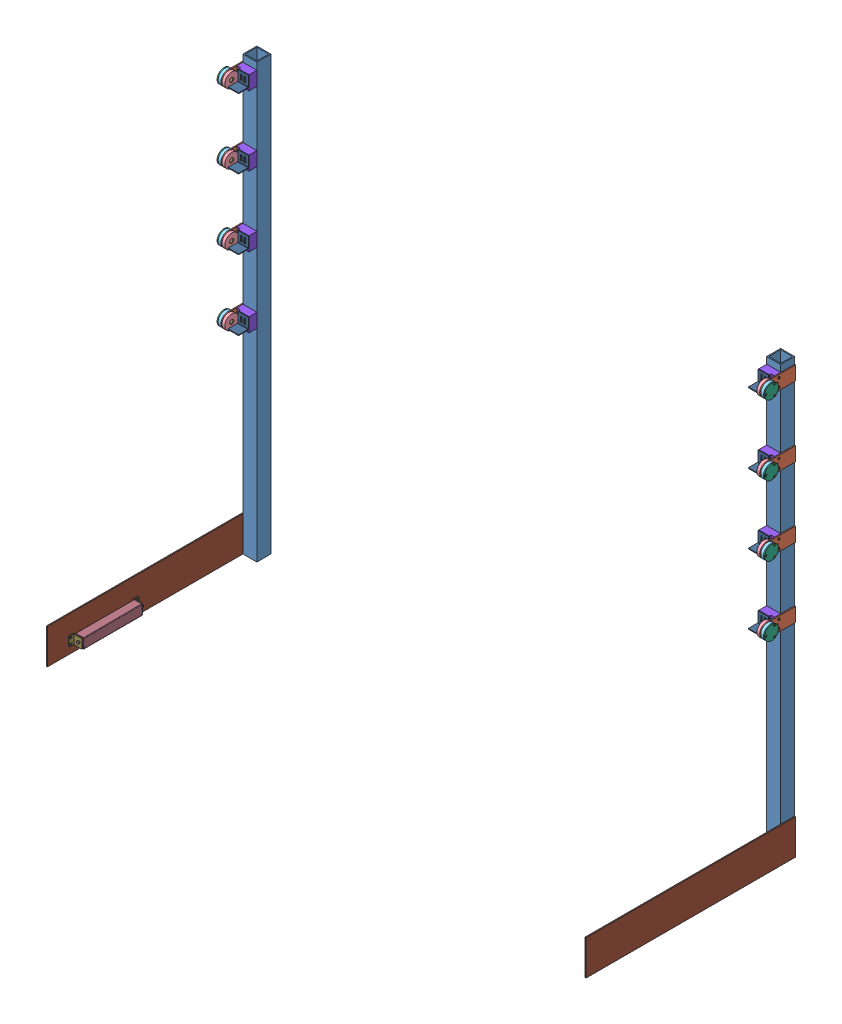
SolidWorks assembly NikeLimbo, configuration Default. Lengths in mm.
Overall size (1571.3 1240 600).
140 component instances, 13 part files, 50 mates.
Components (placement in the parent):
- Frame-1: Frame [Default] at (-24.774 0 -3.5462) size (40 1240 40)
- Frame-2: Frame [Default] at (1475.226 0 -3.5462) size (40 1240 40)
- PoleMount-1: PoleMount [Default] at (-47.774 1005.7046 22.3106) x (0 0 -1) z (0 -1 0) size (100 55.65 40)
  - LEDFixture-1: LEDFixture [Default] at (-4.1432 0 5.1297) size (100 3 40)
  - LED-1: LED [Default] at (-34.1432 3 5.1297) x (0 0 1) z (-1 0 0) size (25 5.3 20)
  - LED-2: LED [Default] at (-34.1432 0 5.1297) x (0 0 -1) z (-1 0 0) size (25 5.3 20)
  - LEDCoverInternal-1: LEDCoverInternal [Default] at origin size (40 8 40)
  - LEDCoverExternal-1: LEDCoverExternal [Default] at origin size (40 8 40)
  - LEDDiffuser-1: LEDDiffuser [Default] at origin size (40 3 40)
  - socket button head screw_iso-1: socket button head screw_iso [ISO 7380 - M3 x 6 --- 6N] at (-25.6432 -12.65 19.8521) x (0 1 0) z (0 0 1) size (7.65 5.7 5.7)
  - socket button head screw_iso-3: socket button head screw_iso [ISO 7380 - M3 x 6 --- 6N] at (-51.1432 -12.65 5.1297) x (0 1 0) z (0 0 1) size (7.65 5.7 5.7)
  - socket button head screw_iso-4: socket button head screw_iso [ISO 7380 - M3 x 6 --- 6N] at (-25.6432 -12.65 -9.5927) x (0 1 0) z (0 0 1) size (7.65 5.7 5.7)
  - MountBlock-1: MountBlock [Default] at origin size (22.5 40 40)
  - hexagon socket button head screw_jis-1: hexagon socket button head screw_jis [JIS B 1174 M3 x 6 (6) --N] at (-2.1432 -1.65 -6.8703) x (0 1 0) z (0 0 1) size (7.65 5.7 5.7)
  - hexagon socket button head screw_jis-2: hexagon socket button head screw_jis [JIS B 1174 M3 x 6 (6) --N] at (-2.1432 -1.65 17.1297) x (0 1 0) z (0 0 1) size (7.65 5.7 5.7)
  - hexagon socket button head screw_jis-3: hexagon socket button head screw_jis [JIS B 1174 M3 x 6 (6) --N] at (-20.2932 23 5.1297) size (7.65 5.7 5.7)
  - hexagon socket button head screw_jis-4: hexagon socket button head screw_jis [JIS B 1174 M3 x 6 (6) --N] at (-20.2932 33 5.1297) size (7.65 5.7 5.7)
- PoleMount-2: PoleMount [Default] at (-47.774 805.4055 22.3106) x (0 0 -1) z (0 -1 0) size (100 55.65 40)
  - LEDFixture-1: LEDFixture [Default] at (-4.1432 0 5.1297) size (100 3 40)
  - LED-1: LED [Default] at (-34.1432 3 5.1297) x (0 0 1) z (-1 0 0) size (25 5.3 20)
  - LED-2: LED [Default] at (-34.1432 0 5.1297) x (0 0 -1) z (-1 0 0) size (25 5.3 20)
  - LEDCoverInternal-1: LEDCoverInternal [Default] at origin size (40 8 40)
  - LEDCoverExternal-1: LEDCoverExternal [Default] at origin size (40 8 40)
  - LEDDiffuser-1: LEDDiffuser [Default] at origin size (40 3 40)
  - socket button head screw_iso-1: socket button head screw_iso [ISO 7380 - M3 x 6 --- 6N] at (-25.6432 -12.65 19.8521) x (0 1 0) z (0 0 1) size (7.65 5.7 5.7)
  - socket button head screw_iso-3: socket button head screw_iso [ISO 7380 - M3 x 6 --- 6N] at (-51.1432 -12.65 5.1297) x (0 1 0) z (0 0 1) size (7.65 5.7 5.7)
  - socket button head screw_iso-4: socket button head screw_iso [ISO 7380 - M3 x 6 --- 6N] at (-25.6432 -12.65 -9.5927) x (0 1 0) z (0 0 1) size (7.65 5.7 5.7)
  - MountBlock-1: MountBlock [Default] at origin size (22.5 40 40)
  - hexagon socket button head screw_jis-1: hexagon socket button head screw_jis [JIS B 1174 M3 x 6 (6) --N] at (-2.1432 -1.65 -6.8703) x (0 1 0) z (0 0 1) size (7.65 5.7 5.7)
  - hexagon socket button head screw_jis-2: hexagon socket button head screw_jis [JIS B 1174 M3 x 6 (6) --N] at (-2.1432 -1.65 17.1297) x (0 1 0) z (0 0 1) size (7.65 5.7 5.7)
  - hexagon socket button head screw_jis-3: hexagon socket button head screw_jis [JIS B 1174 M3 x 6 (6) --N] at (-20.2932 23 5.1297) size (7.65 5.7 5.7)
  - hexagon socket button head screw_jis-4: hexagon socket button head screw_jis [JIS B 1174 M3 x 6 (6) --N] at (-20.2932 33 5.1297) size (7.65 5.7 5.7)
- PoleMount-3: PoleMount [Default] at (-47.774 604.8405 22.3106) x (0 0 -1) z (0 -1 0) size (100 55.65 40)
  - LEDFixture-1: LEDFixture [Default] at (-4.1432 0 5.1297) size (100 3 40)
  - LED-1: LED [Default] at (-34.1432 3 5.1297) x (0 0 1) z (-1 0 0) size (25 5.3 20)
  - LED-2: LED [Default] at (-34.1432 0 5.1297) x (0 0 -1) z (-1 0 0) size (25 5.3 20)
  - LEDCoverInternal-1: LEDCoverInternal [Default] at origin size (40 8 40)
  - LEDCoverExternal-1: LEDCoverExternal [Default] at origin size (40 8 40)
  - LEDDiffuser-1: LEDDiffuser [Default] at origin size (40 3 40)
  - socket button head screw_iso-1: socket button head screw_iso [ISO 7380 - M3 x 6 --- 6N] at (-25.6432 -12.65 19.8521) x (0 1 0) z (0 0 1) size (7.65 5.7 5.7)
  - socket button head screw_iso-3: socket button head screw_iso [ISO 7380 - M3 x 6 --- 6N] at (-51.1432 -12.65 5.1297) x (0 1 0) z (0 0 1) size (7.65 5.7 5.7)
  - socket button head screw_iso-4: socket button head screw_iso [ISO 7380 - M3 x 6 --- 6N] at (-25.6432 -12.65 -9.5927) x (0 1 0) z (0 0 1) size (7.65 5.7 5.7)
  - MountBlock-1: MountBlock [Default] at origin size (22.5 40 40)
  - hexagon socket button head screw_jis-1: hexagon socket button head screw_jis [JIS B 1174 M3 x 6 (6) --N] at (-2.1432 -1.65 -6.8703) x (0 1 0) z (0 0 1) size (7.65 5.7 5.7)
  - hexagon socket button head screw_jis-2: hexagon socket button head screw_jis [JIS B 1174 M3 x 6 (6) --N] at (-2.1432 -1.65 17.1297) x (0 1 0) z (0 0 1) size (7.65 5.7 5.7)
  - hexagon socket button head screw_jis-3: hexagon socket button head screw_jis [JIS B 1174 M3 x 6 (6) --N] at (-20.2932 23 5.1297) size (7.65 5.7 5.7)
  - hexagon socket button head screw_jis-4: hexagon socket button head screw_jis [JIS B 1174 M3 x 6 (6) --N] at (-20.2932 33 5.1297) size (7.65 5.7 5.7)
- PoleMount-4: PoleMount [Default] at (-47.774 1204.953 22.3106) x (0 0 -1) z (0 -1 0) size (100 55.65 40)
  - LEDFixture-1: LEDFixture [Default] at (-4.1432 0 5.1297) size (100 3 40)
  - LED-1: LED [Default] at (-34.1432 3 5.1297) x (0 0 1) z (-1 0 0) size (25 5.3 20)
  - LED-2: LED [Default] at (-34.1432 0 5.1297) x (0 0 -1) z (-1 0 0) size (25 5.3 20)
  - LEDCoverInternal-1: LEDCoverInternal [Default] at origin size (40 8 40)
  - LEDCoverExternal-1: LEDCoverExternal [Default] at origin size (40 8 40)
  - LEDDiffuser-1: LEDDiffuser [Default] at origin size (40 3 40)
  - socket button head screw_iso-1: socket button head screw_iso [ISO 7380 - M3 x 6 --- 6N] at (-25.6432 -12.65 19.8521) x (0 1 0) z (0 0 1) size (7.65 5.7 5.7)
  - socket button head screw_iso-3: socket button head screw_iso [ISO 7380 - M3 x 6 --- 6N] at (-51.1432 -12.65 5.1297) x (0 1 0) z (0 0 1) size (7.65 5.7 5.7)
  - socket button head screw_iso-4: socket button head screw_iso [ISO 7380 - M3 x 6 --- 6N] at (-25.6432 -12.65 -9.5927) x (0 1 0) z (0 0 1) size (7.65 5.7 5.7)
  - MountBlock-1: MountBlock [Default] at origin size (22.5 40 40)
  - hexagon socket button head screw_jis-1: hexagon socket button head screw_jis [JIS B 1174 M3 x 6 (6) --N] at (-2.1432 -1.65 -6.8703) x (0 1 0) z (0 0 1) size (7.65 5.7 5.7)
  - hexagon socket button head screw_jis-2: hexagon socket button head screw_jis [JIS B 1174 M3 x 6 (6) --N] at (-2.1432 -1.65 17.1297) x (0 1 0) z (0 0 1) size (7.65 5.7 5.7)
  - hexagon socket button head screw_jis-3: hexagon socket button head screw_jis [JIS B 1174 M3 x 6 (6) --N] at (-20.2932 23 5.1297) size (7.65 5.7 5.7)
  - hexagon socket button head screw_jis-4: hexagon socket button head screw_jis [JIS B 1174 M3 x 6 (6) --N] at (-20.2932 33 5.1297) size (7.65 5.7 5.7)
- PoleMount-5: PoleMount [Default] at (1498.226 1195.5695 22.3106) x (0 0 -1) z (0 1 0) size (100 55.65 40)
  - LEDFixture-1: LEDFixture [Default] at (-4.1432 0 5.1297) size (100 3 40)
  - LED-1: LED [Default] at (-34.1432 3 5.1297) x (0 0 1) z (-1 0 0) size (25 5.3 20)
  - LED-2: LED [Default] at (-34.1432 0 5.1297) x (0 0 -1) z (-1 0 0) size (25 5.3 20)
  - LEDCoverInternal-1: LEDCoverInternal [Default] at origin size (40 8 40)
  - LEDCoverExternal-1: LEDCoverExternal [Default] at origin size (40 8 40)
  - LEDDiffuser-1: LEDDiffuser [Default] at origin size (40 3 40)
  - socket button head screw_iso-1: socket button head screw_iso [ISO 7380 - M3 x 6 --- 6N] at (-25.6432 -12.65 19.8521) x (0 1 0) z (0 0 1) size (7.65 5.7 5.7)
  - socket button head screw_iso-3: socket button head screw_iso [ISO 7380 - M3 x 6 --- 6N] at (-51.1432 -12.65 5.1297) x (0 1 0) z (0 0 1) size (7.65 5.7 5.7)
  - socket button head screw_iso-4: socket button head screw_iso [ISO 7380 - M3 x 6 --- 6N] at (-25.6432 -12.65 -9.5927) x (0 1 0) z (0 0 1) size (7.65 5.7 5.7)
  - MountBlock-1: MountBlock [Default] at origin size (22.5 40 40)
  - hexagon socket button head screw_jis-1: hexagon socket button head screw_jis [JIS B 1174 M3 x 6 (6) --N] at (-2.1432 -1.65 -6.8703) x (0 1 0) z (0 0 1) size (7.65 5.7 5.7)
  - hexagon socket button head screw_jis-2: hexagon socket button head screw_jis [JIS B 1174 M3 x 6 (6) --N] at (-2.1432 -1.65 17.1297) x (0 1 0) z (0 0 1) size (7.65 5.7 5.7)
  - hexagon socket button head screw_jis-3: hexagon socket button head screw_jis [JIS B 1174 M3 x 6 (6) --N] at (-20.2932 23 5.1297) size (7.65 5.7 5.7)
  - hexagon socket button head screw_jis-4: hexagon socket button head screw_jis [JIS B 1174 M3 x 6 (6) --N] at (-20.2932 33 5.1297) size (7.65 5.7 5.7)
- PoleMount-6: PoleMount [Default] at (1498.226 995.3084 22.3106) x (0 0 -1) z (0 1 0) size (100 55.65 40)
  - LEDFixture-1: LEDFixture [Default] at (-4.1432 0 5.1297) size (100 3 40)
  - LED-1: LED [Default] at (-34.1432 3 5.1297) x (0 0 1) z (-1 0 0) size (25 5.3 20)
  - LED-2: LED [Default] at (-34.1432 0 5.1297) x (0 0 -1) z (-1 0 0) size (25 5.3 20)
  - LEDCoverInternal-1: LEDCoverInternal [Default] at origin size (40 8 40)
  - LEDCoverExternal-1: LEDCoverExternal [Default] at origin size (40 8 40)
  - LEDDiffuser-1: LEDDiffuser [Default] at origin size (40 3 40)
  - socket button head screw_iso-1: socket button head screw_iso [ISO 7380 - M3 x 6 --- 6N] at (-25.6432 -12.65 19.8521) x (0 1 0) z (0 0 1) size (7.65 5.7 5.7)
  - socket button head screw_iso-3: socket button head screw_iso [ISO 7380 - M3 x 6 --- 6N] at (-51.1432 -12.65 5.1297) x (0 1 0) z (0 0 1) size (7.65 5.7 5.7)
  - socket button head screw_iso-4: socket button head screw_iso [ISO 7380 - M3 x 6 --- 6N] at (-25.6432 -12.65 -9.5927) x (0 1 0) z (0 0 1) size (7.65 5.7 5.7)
  - MountBlock-1: MountBlock [Default] at origin size (22.5 40 40)
  - hexagon socket button head screw_jis-1: hexagon socket button head screw_jis [JIS B 1174 M3 x 6 (6) --N] at (-2.1432 -1.65 -6.8703) x (0 1 0) z (0 0 1) size (7.65 5.7 5.7)
  - hexagon socket button head screw_jis-2: hexagon socket button head screw_jis [JIS B 1174 M3 x 6 (6) --N] at (-2.1432 -1.65 17.1297) x (0 1 0) z (0 0 1) size (7.65 5.7 5.7)
  - hexagon socket button head screw_jis-3: hexagon socket button head screw_jis [JIS B 1174 M3 x 6 (6) --N] at (-20.2932 23 5.1297) size (7.65 5.7 5.7)
  - hexagon socket button head screw_jis-4: hexagon socket button head screw_jis [JIS B 1174 M3 x 6 (6) --N] at (-20.2932 33 5.1297) size (7.65 5.7 5.7)
- PoleMount-7: PoleMount [Default] at (1498.226 795.7577 22.3106) x (0 0 -1) z (0 1 0) size (100 55.65 40)
  - LEDFixture-1: LEDFixture [Default] at (-4.1432 0 5.1297) size (100 3 40)
  - LED-1: LED [Default] at (-34.1432 3 5.1297) x (0 0 1) z (-1 0 0) size (25 5.3 20)
  - LED-2: LED [Default] at (-34.1432 0 5.1297) x (0 0 -1) z (-1 0 0) size (25 5.3 20)
  - LEDCoverInternal-1: LEDCoverInternal [Default] at origin size (40 8 40)
  - LEDCoverExternal-1: LEDCoverExternal [Default] at origin size (40 8 40)
  - LEDDiffuser-1: LEDDiffuser [Default] at origin size (40 3 40)
  - socket button head screw_iso-1: socket button head screw_iso [ISO 7380 - M3 x 6 --- 6N] at (-25.6432 -12.65 19.8521) x (0 1 0) z (0 0 1) size (7.65 5.7 5.7)
  - socket button head screw_iso-3: socket button head screw_iso [ISO 7380 - M3 x 6 --- 6N] at (-51.1432 -12.65 5.1297) x (0 1 0) z (0 0 1) size (7.65 5.7 5.7)
  - socket button head screw_iso-4: socket button head screw_iso [ISO 7380 - M3 x 6 --- 6N] at (-25.6432 -12.65 -9.5927) x (0 1 0) z (0 0 1) size (7.65 5.7 5.7)
  - MountBlock-1: MountBlock [Default] at origin size (22.5 40 40)
  - hexagon socket button head screw_jis-1: hexagon socket button head screw_jis [JIS B 1174 M3 x 6 (6) --N] at (-2.1432 -1.65 -6.8703) x (0 1 0) z (0 0 1) size (7.65 5.7 5.7)
  - hexagon socket button head screw_jis-2: hexagon socket button head screw_jis [JIS B 1174 M3 x 6 (6) --N] at (-2.1432 -1.65 17.1297) x (0 1 0) z (0 0 1) size (7.65 5.7 5.7)
  - hexagon socket button head screw_jis-3: hexagon socket button head screw_jis [JIS B 1174 M3 x 6 (6) --N] at (-20.2932 23 5.1297) size (7.65 5.7 5.7)
  - hexagon socket button head screw_jis-4: hexagon socket button head screw_jis [JIS B 1174 M3 x 6 (6) --N] at (-20.2932 33 5.1297) size (7.65 5.7 5.7)
- PoleMount-8: PoleMount [Default] at (1498.226 596.7779 22.3106) x (0 0 -1) z (0 1 0) size (100 55.65 40)
  - LEDFixture-1: LEDFixture [Default] at (-4.1432 0 5.1297) size (100 3 40)
  - LED-1: LED [Default] at (-34.1432 3 5.1297) x (0 0 1) z (-1 0 0) size (25 5.3 20)
  - LED-2: LED [Default] at (-34.1432 0 5.1297) x (0 0 -1) z (-1 0 0) size (25 5.3 20)
  - LEDCoverInternal-1: LEDCoverInternal [Default] at origin size (40 8 40)
  - LEDCoverExternal-1: LEDCoverExternal [Default] at origin size (40 8 40)
  - LEDDiffuser-1: LEDDiffuser [Default] at origin size (40 3 40)
  - socket button head screw_iso-1: socket button head screw_iso [ISO 7380 - M3 x 6 --- 6N] at (-25.6432 -12.65 19.8521) x (0 1 0) z (0 0 1) size (7.65 5.7 5.7)
  - socket button head screw_iso-3: socket button head screw_iso [ISO 7380 - M3 x 6 --- 6N] at (-51.1432 -12.65 5.1297) x (0 1 0) z (0 0 1) size (7.65 5.7 5.7)
  - socket button head screw_iso-4: socket button head screw_iso [ISO 7380 - M3 x 6 --- 6N] at (-25.6432 -12.65 -9.5927) x (0 1 0) z (0 0 1) size (7.65 5.7 5.7)
  - MountBlock-1: MountBlock [Default] at origin size (22.5 40 40)
  - hexagon socket button head screw_jis-1: hexagon socket button head screw_jis [JIS B 1174 M3 x 6 (6) --N] at (-2.1432 -1.65 -6.8703) x (0 1 0) z (0 0 1) size (7.65 5.7 5.7)
  - hexagon socket button head screw_jis-2: hexagon socket button head screw_jis [JIS B 1174 M3 x 6 (6) --N] at (-2.1432 -1.65 17.1297) x (0 1 0) z (0 0 1) size (7.65 5.7 5.7)
  - hexagon socket button head screw_jis-3: hexagon socket button head screw_jis [JIS B 1174 M3 x 6 (6) --N] at (-20.2932 23 5.1297) size (7.65 5.7 5.7)
  - hexagon socket button head screw_jis-4: hexagon socket button head screw_jis [JIS B 1174 M3 x 6 (6) --N] at (-20.2932 33 5.1297) size (7.65 5.7 5.7)
- PoleTray-2: PoleTray [Default] at (-19.774 1204.8233 40.9538) x (1 0 0) z (0 -1 0) size (30 30 32)
- PoleTray-3: PoleTray [Default] at (-19.774 1005.5749 40.9538) x (1 0 0) z (0 -1 0) size (30 30 32)
- PoleTray-4: PoleTray [Default] at (-19.774 805.2758 40.9538) x (1 0 0) z (0 -1 0) size (30 30 32)
- PoleTray-5: PoleTray [Default] at (-19.774 604.7108 40.9538) x (1 0 0) z (0 -1 0) size (30 30 32)
- PoleTray-6: PoleTray [Default] at (1470.226 1205.6992 40.9538) x (1 0 0) z (0 -1 0) size (30 30 32)
- PoleTray-7: PoleTray [Default] at (1470.226 1005.4381 40.9538) x (1 0 0) z (0 -1 0) size (30 30 32)
- PoleTray-8: PoleTray [Default] at (1470.226 805.8874 40.9538) x (1 0 0) z (0 -1 0) size (30 30 32)
- PoleTray-9: PoleTray [Default] at (1470.226 606.9077 40.9538) x (1 0 0) z (0 -1 0) size (30 30 32)
- SideWing-1: SideWing [Default] at origin size (3 100 600)
- SideWing-2: SideWing [Default] at (-1543 0 0) size (3 100 600)
- AreaSensor-1: AreaSensor [Default] at (1490.526 8.0423 389.3818) x (0 0 -1) z (0 1 0) size (200 27.3 28.6)
  - AreaSensorBracket-1: AreaSensorBracket [Default] at (-80.7618 7.8 15.7103) x (0 0 1) z (0 -1 0) size (26.6 15 25)
  - AreaSensorBracket-2: AreaSensorBracket [Default] at (89.2382 7.8 15.7103) x (0 0 -1) z (0 -1 0) size (26.6 15 25)
  - AreaSensorBW40-04-2: AreaSensorBW40-04 [Default] at (4.2382 0 15.7103) size (185 22.6 28.6)
- AreaSensor-2: AreaSensor [Default] at (-40.074 48.5699 420.0646) x (0 0 -1) z (0 -1 0) size (200 27.3 28.6)
  - AreaSensorBracket-1: AreaSensorBracket [Default] at (-80.7618 7.8 15.7103) x (0 0 1) z (0 -1 0) size (26.6 15 25)
  - AreaSensorBracket-2: AreaSensorBracket [Default] at (89.2382 7.8 15.7103) x (0 0 -1) z (0 -1 0) size (26.6 15 25)
  - AreaSensorBW40-04-2: AreaSensorBW40-04 [Default] at (4.2382 0 15.7103) size (185 22.6 28.6)
Mates (geometry in assembly coordinates):
- Coincident1: coincident aligned: plane of Frame-1 through (-4.774 1240 16.4538) normal (0 0 1); plane of Frame-2 through (1495.226 1240 16.4538) normal (0 0 1)
- Coincident2: coincident aligned: plane of Frame-1 through (-44.774 1240 -23.5462) normal (0 1 0); plane of Frame-2 through (1455.226 1240 -23.5462) normal (0 1 0)
- Distance1: distance = 1460 mm anti-aligned: plane of Frame-1 through (-4.774 1240 16.4538) normal (1 0 0); plane of Frame-2 through (1455.226 1240 16.4538) normal (-1 0 0)
- Coincident4: coincident anti-aligned: plane of Frame-1 through (-44.774 1240 16.4538) normal (-1 0 0); plane of PoleMount-1/LEDFixture-1 through (-44.774 1000.5749 56.4538) normal (1 0 0)
- Coincident5: coincident anti-aligned: plane of Frame-1 through (-4.774 1240 16.4538) normal (0 0 1); plane of PoleMount-1/MountBlock-1 through (-4.774 1020.5749 16.4538) normal (0 0 -1)
- Coincident6: coincident anti-aligned: plane of Frame-1 through (-44.774 1240 16.4538) normal (-1 0 0); plane of PoleMount-2/LEDFixture-1 through (-44.774 800.2758 56.4538) normal (1 0 0)
- Coincident7: coincident anti-aligned: plane of Frame-1 through (-4.774 1240 16.4538) normal (0 0 1); plane of PoleMount-2/MountBlock-1 through (-4.774 820.2758 16.4538) normal (0 0 -1)
- Coincident8: coincident anti-aligned: plane of Frame-1 through (-44.774 1240 16.4538) normal (-1 0 0); plane of PoleMount-3/LEDFixture-1 through (-44.774 599.7108 56.4538) normal (1 0 0)
- Coincident9: coincident anti-aligned: plane of Frame-1 through (-4.774 1240 16.4538) normal (0 0 1); plane of PoleMount-3/MountBlock-1 through (-4.774 619.7108 16.4538) normal (0 0 -1)
- Coincident10: coincident anti-aligned: plane of Frame-1 through (-44.774 1240 16.4538) normal (-1 0 0); plane of PoleMount-4/LEDFixture-1 through (-44.774 1199.8233 56.4538) normal (1 0 0)
- Coincident11: coincident anti-aligned: plane of Frame-1 through (-4.774 1240 16.4538) normal (0 0 1); plane of PoleMount-4/MountBlock-1 through (-4.774 1219.8233 16.4538) normal (0 0 -1)
- Coincident12: coincident anti-aligned: plane of Frame-2 through (1495.226 1240 16.4538) normal (1 0 0); plane of PoleMount-5/LEDFixture-1 through (1495.226 1200.6992 56.4538) normal (-1 0 0)
- Coincident13: coincident anti-aligned: plane of Frame-2 through (1495.226 1240 16.4538) normal (0 0 1); plane of PoleMount-5/MountBlock-1 through (1455.226 1180.6992 16.4538) normal (0 0 -1)
- Coincident14: coincident anti-aligned: plane of Frame-2 through (1495.226 1240 16.4538) normal (1 0 0); plane of PoleMount-6/LEDFixture-1 through (1495.226 1000.4381 56.4538) normal (-1 0 0)
- Coincident15: coincident anti-aligned: plane of Frame-2 through (1495.226 1240 16.4538) normal (0 0 1); plane of PoleMount-6/MountBlock-1 through (1455.226 980.4381 16.4538) normal (0 0 -1)
- Coincident16: coincident anti-aligned: plane of Frame-2 through (1495.226 1240 16.4538) normal (1 0 0); plane of PoleMount-7/LEDFixture-1 through (1495.226 800.8874 56.4538) normal (-1 0 0)
- Coincident17: coincident anti-aligned: plane of Frame-2 through (1495.226 1240 16.4538) normal (0 0 1); plane of PoleMount-7/MountBlock-1 through (1455.226 780.8874 16.4538) normal (0 0 -1)
- Coincident18: coincident anti-aligned: plane of Frame-2 through (1495.226 1240 16.4538) normal (1 0 0); plane of PoleMount-8/LEDFixture-1 through (1495.226 601.9077 56.4538) normal (-1 0 0)
- Coincident19: coincident anti-aligned: plane of Frame-2 through (1495.226 1240 16.4538) normal (0 0 1); plane of PoleMount-8/MountBlock-1 through (1455.226 581.9077 16.4538) normal (0 0 -1)
- Coincident20: coincident anti-aligned: plane of PoleMount-4/MountBlock-1 through (-4.774 1219.8233 38.9538) normal (0 0 1); plane of PoleTray-2 through (-34.774 1219.8233 38.9538) normal (0 0 -1)
- Coincident21: coincident aligned: plane of PoleMount-4/MountBlock-1 through (-4.774 1179.8233 16.4538) normal (1 0 0); plane of PoleTray-2 through (-4.774 1189.8233 38.9538) normal (1 0 0)
- Coincident22: coincident aligned: plane of PoleMount-4/MountBlock-1 through (-4.774 1219.8233 16.4538) normal (0 1 0); plane of PoleTray-2 through (-4.774 1219.8233 38.9538) normal (0 1 0)
- Coincident23: coincident anti-aligned: plane of PoleMount-1/MountBlock-1 through (-4.774 1020.5749 38.9538) normal (0 0 1); plane of PoleTray-3 through (-34.774 1020.5749 38.9538) normal (0 0 -1)
- Coincident25: coincident aligned: plane of PoleMount-1/MountBlock-1 through (-4.774 980.5749 16.4538) normal (1 0 0); plane of PoleTray-3 through (-4.774 990.5749 38.9538) normal (1 0 0)
- Coincident26: coincident aligned: plane of PoleMount-1/MountBlock-1 through (-4.774 1020.5749 16.4538) normal (0 1 0); plane of PoleTray-3 through (-4.774 1020.5749 38.9538) normal (0 1 0)
- Coincident27: coincident anti-aligned: plane of PoleMount-2/MountBlock-1 through (-4.774 820.2758 38.9538) normal (0 0 1); plane of PoleTray-4 through (-34.774 820.2758 38.9538) normal (0 0 -1)
- Coincident28: coincident aligned: plane of PoleMount-2/MountBlock-1 through (-4.774 780.2758 16.4538) normal (1 0 0); plane of PoleTray-4 through (-4.774 790.2758 38.9538) normal (1 0 0)
- Coincident29: coincident aligned: plane of PoleMount-2/MountBlock-1 through (-4.774 820.2758 16.4538) normal (0 1 0); plane of PoleTray-4 through (-4.774 820.2758 38.9538) normal (0 1 0)
- Coincident30: coincident anti-aligned: plane of PoleMount-3/MountBlock-1 through (-4.774 619.7108 38.9538) normal (0 0 1); plane of PoleTray-5 through (-34.774 619.7108 38.9538) normal (0 0 -1)
- Coincident31: coincident aligned: plane of PoleMount-3/MountBlock-1 through (-4.774 579.7108 16.4538) normal (1 0 0); plane of PoleTray-5 through (-4.774 589.7108 38.9538) normal (1 0 0)
- Coincident32: coincident aligned: plane of PoleMount-3/MountBlock-1 through (-4.774 619.7108 16.4538) normal (0 1 0); plane of PoleTray-5 through (-4.774 619.7108 38.9538) normal (0 1 0)
- Coincident33: coincident anti-aligned: plane of PoleMount-5/MountBlock-1 through (1455.226 1180.6992 38.9538) normal (0 0 1); plane of PoleTray-6 through (1455.226 1220.6992 38.9538) normal (0 0 -1)
- Coincident34: coincident anti-aligned: plane of PoleMount-6/MountBlock-1 through (1455.226 980.4381 38.9538) normal (0 0 1); plane of PoleTray-7 through (1455.226 1020.4381 38.9538) normal (0 0 -1)
- Coincident35: coincident anti-aligned: plane of PoleMount-7/MountBlock-1 through (1455.226 780.8874 38.9538) normal (0 0 1); plane of PoleTray-8 through (1455.226 820.8874 38.9538) normal (0 0 -1)
- Coincident36: coincident anti-aligned: plane of PoleMount-8/MountBlock-1 through (1455.226 581.9077 38.9538) normal (0 0 1); plane of PoleTray-9 through (1455.226 621.9077 38.9538) normal (0 0 -1)
- Coincident37: coincident aligned: plane of PoleMount-8/MountBlock-1 through (1455.226 621.9077 16.4538) normal (-1 0 0); plane of PoleTray-9 through (1455.226 591.9077 38.9538) normal (-1 0 0)
- Coincident38: coincident aligned: plane of PoleMount-8/MountBlock-1 through (1455.226 621.9077 16.4538) normal (0 1 0); plane of PoleTray-9 through (1485.226 621.9077 38.9538) normal (0 1 0)
- Coincident39: coincident aligned: plane of PoleMount-7/MountBlock-1 through (1455.226 820.8874 16.4538) normal (0 1 0); plane of PoleTray-8 through (1485.226 820.8874 38.9538) normal (0 1 0)
- Coincident40: coincident aligned: plane of PoleMount-7/MountBlock-1 through (1455.226 820.8874 16.4538) normal (-1 0 0); plane of PoleTray-8 through (1455.226 790.8874 38.9538) normal (-1 0 0)
- Coincident41: coincident aligned: plane of PoleMount-6/MountBlock-1 through (1455.226 1020.4381 16.4538) normal (0 1 0); plane of PoleTray-7 through (1485.226 1020.4381 38.9538) normal (0 1 0)
- Coincident42: coincident aligned: plane of PoleMount-6/MountBlock-1 through (1455.226 1020.4381 16.4538) normal (-1 0 0); plane of PoleTray-7 through (1455.226 990.4381 38.9538) normal (-1 0 0)
- Coincident43: coincident aligned: plane of PoleMount-5/MountBlock-1 through (1455.226 1220.6992 16.4538) normal (0 1 0); plane of PoleTray-6 through (1485.226 1220.6992 38.9538) normal (0 1 0)
- Coincident44: coincident aligned: plane of PoleMount-5/MountBlock-1 through (1455.226 1220.6992 16.4538) normal (-1 0 0); plane of PoleTray-6 through (1455.226 1190.6992 38.9538) normal (-1 0 0)
- Coincident45: coincident anti-aligned: plane of Frame-1 through (-44.774 1240 16.4538) normal (-1 0 0); plane of SideWing-2 through (-44.774 100 -23.5462) normal (1 0 0)
- Coincident46: coincident aligned: plane of Frame-1 through (-4.774 1240 -23.5462) normal (0 0 -1); plane of SideWing-2 through (-44.774 0 -23.5462) normal (0 0 -1)
- Coincident47: coincident aligned: plane of Frame-1 through (-44.774 0 -23.5462) normal (0 -1 0); plane of SideWing-2 through (-44.774 0 -23.5462) normal (0 -1 0)
- Coincident48: coincident anti-aligned: plane of SideWing-1 through (1495.226 100 -23.5462) normal (-1 0 0); plane of AreaSensor-1/AreaSensorBracket-1 through (1495.226 37.0526 472.1436) normal (1 0 0)
- Coincident49: coincident anti-aligned: plane of SideWing-2 through (-44.774 100 -23.5462) normal (1 0 0); plane of AreaSensor-2/AreaSensorBracket-1 through (-44.774 19.5596 502.8264) normal (-1 0 0)
- Parallel1: parallel aligned: plane of SideWing-1 through (1498.226 100 -23.5462) normal (0 1 0); plane of AreaSensor-1/AreaSensorBW40-04-2 through (1467.926 38.0526 300.1436) normal (0 1 0)
- Parallel2: parallel aligned: plane of SideWing-2 through (-44.774 100 -23.5462) normal (0 1 0); plane of AreaSensor-2/AreaSensorBW40-04-2 through (-17.474 47.1596 330.8264) normal (0 1 0)
